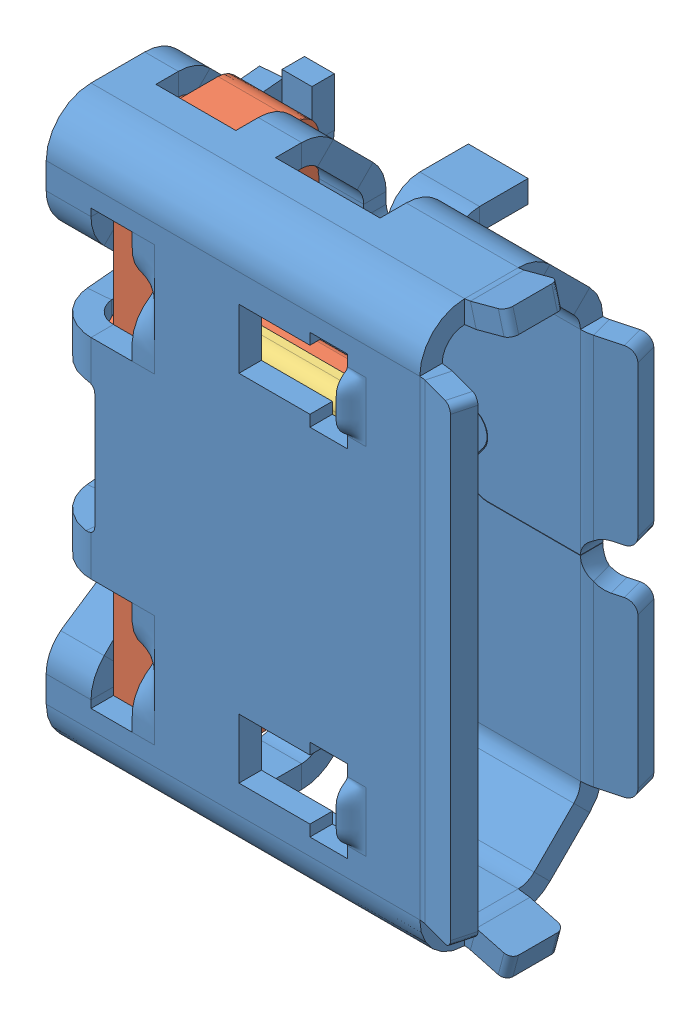
SolidWorks assembly micro_usb_connector, configuration Default. Lengths in mm.
Overall size (5.84 7.77 3.4).
8 component instances, 4 part files, 0 mates.
Components (placement in the parent):
- shield.stp-1: shield.stp [Default] at origin size (5.84 7.77 3.4)
- socket_housing.stp-1: socket_housing.stp [Default] at origin size (4.25 6.85 2.15)
- socket_plate.stp-1: socket_plate.stp [Default] at origin size (3.38 6.8 0.31)
- terminal.stp-1: terminal.stp [Default] at origin size (3.22 0.35 1.72)
- terminal.stp-2: terminal.stp [Default] at (0 -1.3 0) size (3.22 0.35 1.72)
- terminal.stp-3: terminal.stp [Default] at (0 -0.65 0) size (3.22 0.35 1.72)
- terminal.stp-4: terminal.stp [Default] at (0 0.65 0) size (3.22 0.35 1.72)
- terminal.stp-5: terminal.stp [Default] at (0 1.3 0) size (3.22 0.35 1.72)
